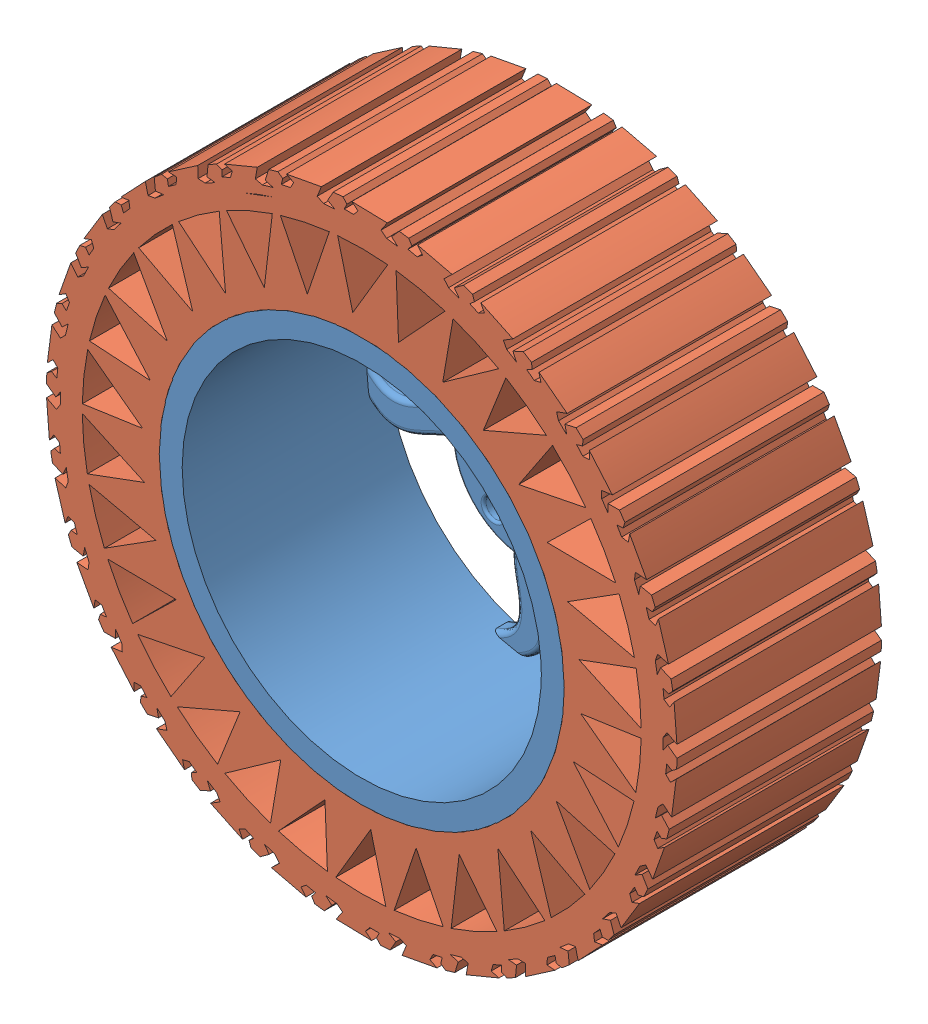
SolidWorks assembly Assem2, configuration Default. Lengths in mm.
Overall size (631.93 632 206.02).
3 component instances, 3 part files, 2 mates.
Components (placement in the parent):
- llanta-1: llanta [Default] at origin size (406 406 206.02)
- neumatico-1: neumatico [Default] at origin size (631.93 632 205)
- tapita-2: tapita [Default] at origin size (60 60 25)
Mates (geometry in assembly coordinates):
- Tangent1: tangent: cylinder of llanta-1 through (0 0 40) axis (0 0 -1) radius 30; cylinder of tapita-2 through (0 0 25) axis (0 0 -1) radius 30
- Tangent2: tangent: cylinder of llanta-1 through (0 0 205) axis (0 0 -1) radius 203; cylinder of neumatico-1 through (0 0 205) axis (0 0 -1) radius 203
